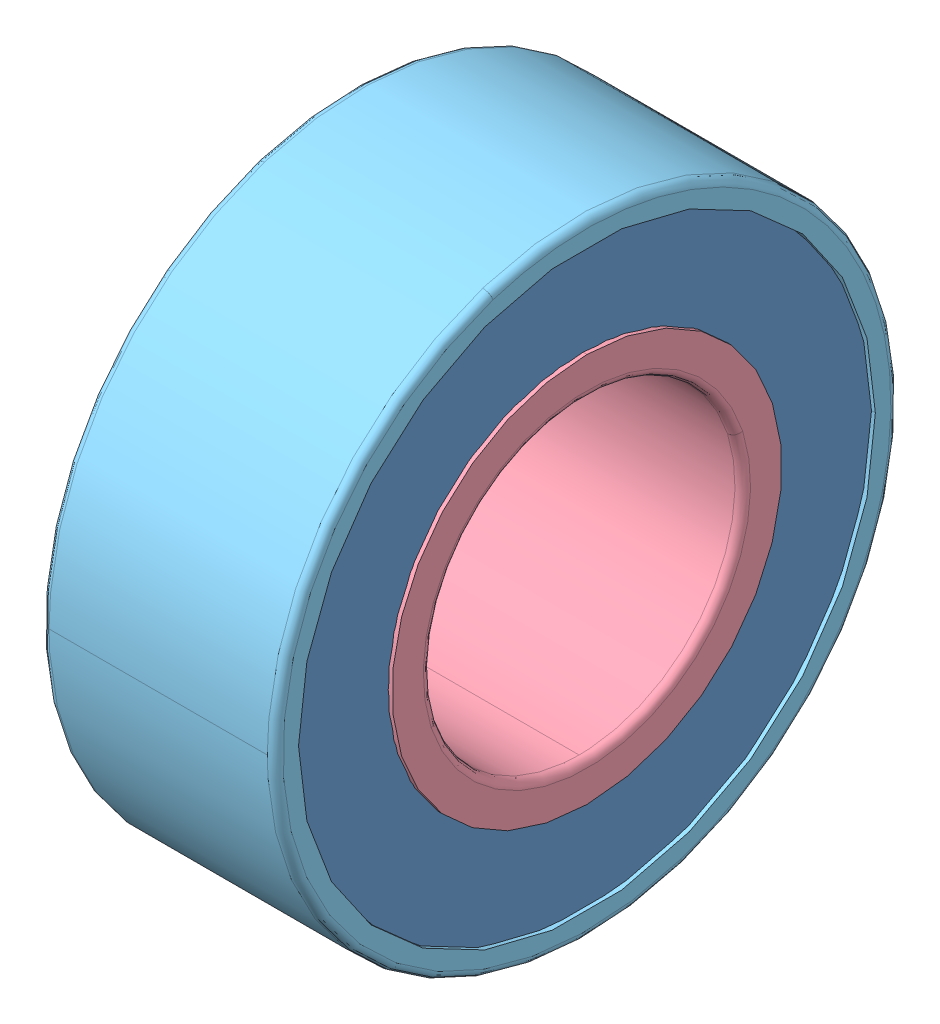
SolidWorks assembly MR84ZZ, configuration Default. Lengths in mm.
Overall size (3 9.83 9.83).
16 component instances, 5 part files, 0 mates.
Components (placement in the parent):
- MR84ZZ_3-1: MR84ZZ_3 [Default] at origin size (0.15 7.4 7.4)
- MR84ZZ_5-1: MR84ZZ_5 [Default] at (1.5 1.5 2.5981) x (1 0 0) z (0 -1 0) size (1.2 1.2 1.2) (hidden)
- MR84ZZ_5-2: MR84ZZ_5 [Default] at (1.5 2.5981 1.5) x (1 0 0) z (0 -1 0) size (1.2 1.2 1.2) (hidden)
- MR84ZZ_5-3: MR84ZZ_5 [Default] at (1.5 3 0) x (1 0 0) z (0 -1 0) size (1.2 1.2 1.2) (hidden)
- MR84ZZ_5-4: MR84ZZ_5 [Default] at (1.5 2.5981 -1.5) x (1 0 0) z (0 -1 0) size (1.2 1.2 1.2) (hidden)
- MR84ZZ_5-5: MR84ZZ_5 [Default] at (1.5 1.5 -2.5981) x (1 0 0) z (0 -1 0) size (1.2 1.2 1.2) (hidden)
- MR84ZZ_5-6: MR84ZZ_5 [Default] at (1.5 0 -3) x (1 0 0) z (0 -1 0) size (1.2 1.2 1.2) (hidden)
- MR84ZZ_5-7: MR84ZZ_5 [Default] at (1.5 -1.5 -2.5981) x (1 0 0) z (0 -1 0) size (1.2 1.2 1.2) (hidden)
- MR84ZZ_5-8: MR84ZZ_5 [Default] at (1.5 -2.5981 -1.5) x (1 0 0) z (0 -1 0) size (1.2 1.2 1.2) (hidden)
- MR84ZZ_5-9: MR84ZZ_5 [Default] at (1.5 -3 0) x (1 0 0) z (0 -1 0) size (1.2 1.2 1.2) (hidden)
- MR84ZZ_5-10: MR84ZZ_5 [Default] at (1.5 -2.5981 1.5) x (1 0 0) z (0 -1 0) size (1.2 1.2 1.2) (hidden)
- MR84ZZ_5-11: MR84ZZ_5 [Default] at (1.5 -1.5 2.5981) x (1 0 0) z (0 -1 0) size (1.2 1.2 1.2) (hidden)
- MR84ZZ_5-12: MR84ZZ_5 [Default] at (1.5 0 3) x (1 0 0) z (0 -1 0) size (1.2 1.2 1.2) (hidden)
- MR84ZZ_18-1: MR84ZZ_18 [Default] at (0.3984 0 0) x (-1 0 0) z (0 -1 0) size (0.15 7.4 7.4)
- MR84ZZ_20-1: MR84ZZ_20 [Default] x (1 0 0) z (0 -1 0) size (3 5.29 5.29)
- MR84ZZ_22-1: MR84ZZ_22 [Default] at origin size (3 9.83 9.83)
